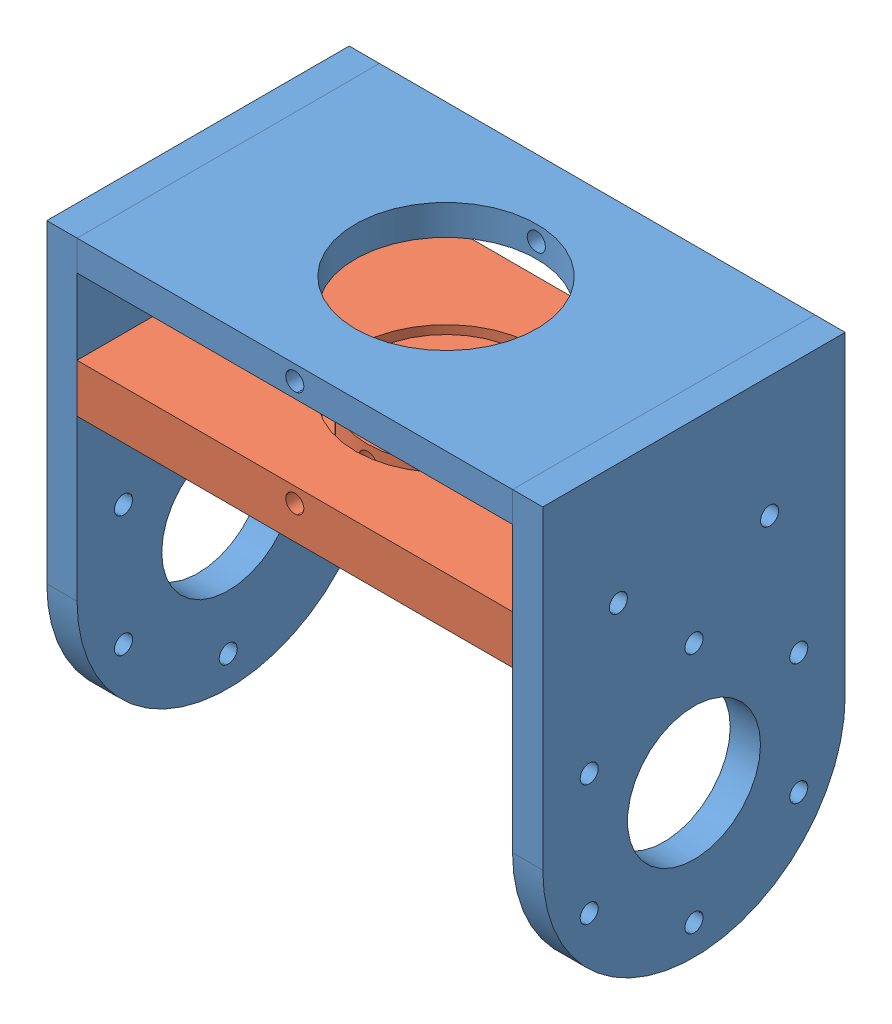
SolidWorks assembly Assemblage_bras, configuration Défaut. Lengths in mm.
Overall size (82 77 50).
2 component instances, 2 part files, 3 mates.
Components (placement in the parent):
- Carcasse_bras-1: Carcasse_bras [Défaut] at (11.615 29.0804 10) size (82 77 50)
- Support_axe-1: Support_axe [Défaut] at (-24.6417 66.9959 57) size (72 8 50)
Mates (geometry in assembly coordinates):
- Coaxiale1: concentric: circle of Carcasse_bras-1; circle of Support_axe-1
- Coaxiale2: concentric: circle of Carcasse_bras-1; circle of Support_axe-1
- Coïncidente3: coincident anti-aligned: plane of Carcasse_bras-1 through (-30.1417 -12.5041 82) normal (1 0 0); plane of Support_axe-1 through (-30.1417 21.9959 107) normal (-1 0 0)
